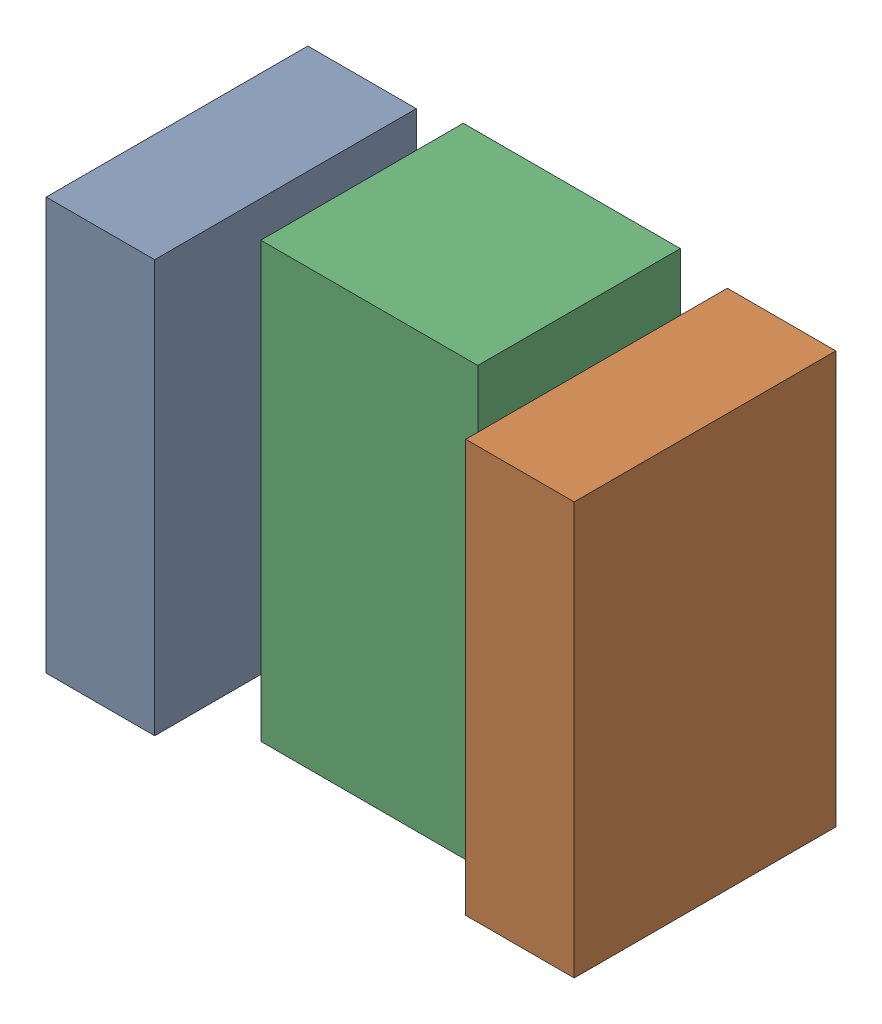
SolidWorks assembly C7_Motor_5Kanaloa_v2.0.0_Motor, configuration Default. Lengths in mm.
Overall size (3.65 3 1.81).
6 component instances, 2 part files, 0 mates.
Components (placement in the parent):
- 334788400-1: 334788400 [Default] at (144.811 84.582 0) size (0.75 2.85 1.81)
  - Extruded_5-1: Extruded_5 [Default] at origin size (0.75 2.85 1.81)
- 334788400-2: 334788400 [Default] at (147.711 84.582 0) size (0.75 2.85 1.81)
  - Extruded_5-1: Extruded_5 [Default] at origin size (0.75 2.85 1.81)
- 334788656-1: 334788656 [Default] at (146.261 84.582 0) size (1.5 3 1.4)
  - Extruded_1-1: Extruded_1 [Default] at origin size (1.5 3 1.4)
